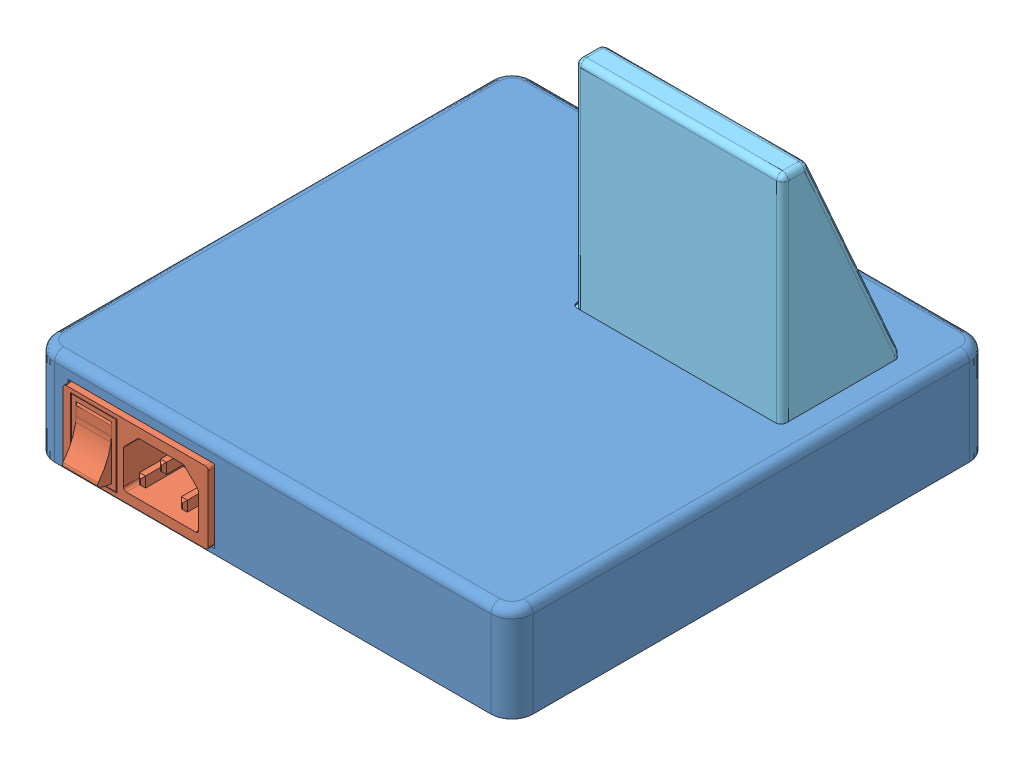
SolidWorks assembly heatplate_case, configuration Default. Lengths in mm.
Overall size (160.13 103.76 166.72).
6 component instances, 6 part files, 13 mates.
Components (placement in the parent):
- case-2: case [Default] at (15.3311 -15.6956 -180.8) size (160.13 32 160)
- IEC-socket+switch-2: IEC-socket+switch [Default] at (-13.1856 2.06 -57.9) x (1 0 0) z (0 0 -1) size (48.6 24 24.72)
- SSR40-2: SSR40 [Default] at (-24.7362 11.3044 -145.0083) x (0 0 -1) z (-1 0 0) size (60 23 46)
- PSU_5V-3: PSU_5V [Default] at (47.6735 14.3044 -98.5113) x (0 0 1) z (1 0 0) size (74.5 28 51)
- case-display-holder-1: case-display-holder [Default] at (69.23 16.7044 -176.9583) x (1 0 0) z (0 0 -1) size (75.5 78.76 60)
- LCD-1: LCD [Default] at (81.3746 13.3913 -195.3412) x (-1 0 0) z (0 0.403846 -0.914827) size (63.15 82.2 5.6) (hidden)
Mates (geometry in assembly coordinates):
- Coincident1: coincident anti-aligned: plane of case-2 through (95.2644 14.3044 -61.5) normal (0 0 1); plane of IEC-socket+switch-2 through (-2.2597 -12.4456 -61.5) normal (0 0 -1)
- Coincident3: coincident anti-aligned: plane of case-2 through (-50.2597 10.5544 -117.7837) normal (0 -1 0); plane of IEC-socket+switch-2 through (-48.8597 10.5544 -61.5) normal (0 1 0)
- Coincident4: coincident anti-aligned: plane of case-2 through (-1.2597 10.5544 -117.7837) normal (-1 0 0); plane of IEC-socket+switch-2 through (-1.2597 -12.4456 -61.5) normal (1 0 0)
- Coincident5: coincident aligned: plane of case-2 through (15.3311 -15.6956 -180.8) normal (0 -1 0); plane of PSU_5V-2 through (1656.1127 -15.6956 878.9867) normal (0 -1 0)
- Coincident8: coincident anti-aligned: plane of case-2 through (15.3311 14.3044 -180.8) normal (0 -1 0); plane of PSU_5V-3 through (47.6735 14.3044 -98.5113) normal (0 1 0)
- Coincident11: coincident anti-aligned: plane of case-2 through (15.3311 11.3044 -180.8) normal (0 -1 0); plane of case-display-holder-1 through (69.23 11.3044 -176.9583) normal (0 1 0)
- Coincident13: coincident anti-aligned: plane of case-2 through (88.2644 -15.6966 -200) normal (-1 0 0); plane of case-display-holder-1 through (88.2644 15.7044 -160.5) normal (1 0 0)
- Coincident14: coincident anti-aligned: plane of case-2 through (18.2644 -15.6966 -200) normal (0 0 1); plane of case-display-holder-1 through (18.7644 15.7044 -200) normal (0 0 -1)
- Parallel2: parallel anti-aligned: plane of case-display-holder-1 through (86.2644 9.3034 -162.5) normal (-1 0 0); plane of LCD-1 through (78.9144 82.1064 -171.1286) normal (1 0 0)
- Distance2: distance = 7.35 mm anti-aligned: plane of LCD-1 through (78.9144 82.1064 -171.1286) normal (1 0 0); plane of case-display-holder-1 through (86.2644 9.3034 -162.5) normal (-1 0 0)
- Parallel3: parallel anti-aligned: plane of case-2 through (95.2644 14.3044 -63) normal (0 0 -1); plane of PSU_5V-3 through (30.6096 -13.6956 -71.9398) normal (0 0 1)
- Coincident15: coincident anti-aligned: plane of case-2 through (-52.3362 11.3044 -160.77) normal (0 -1 0); plane of SSR40-2 through (-24.7362 11.3044 -145.0083) normal (0 1 0)
- Parallel4: parallel anti-aligned: plane of case-2 through (-58.7356 14.3044 -63) normal (1 0 0); plane of SSR40-2 through (-52.3362 -11.6956 -100.77) normal (-1 0 0)
